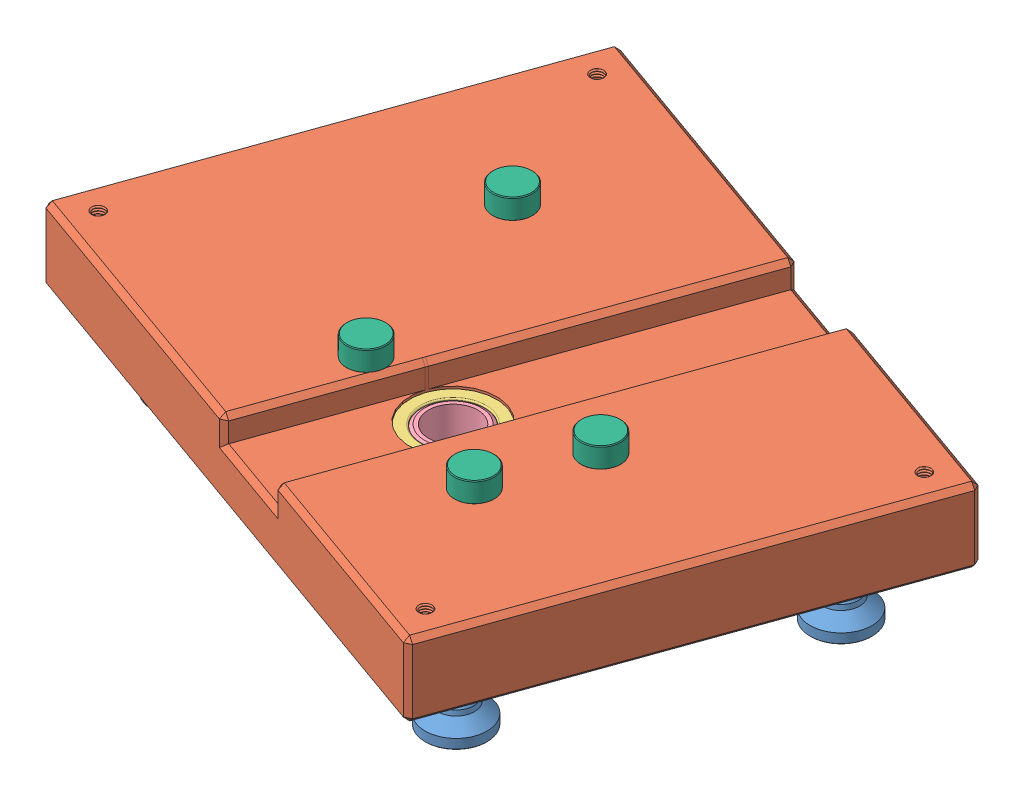
SolidWorks assembly Base Assembly, configuration Default. Lengths in mm.
Overall size (288.96 65.67 252.42).
13 component instances, 6 part files, 20 mates.
Components (placement in the parent):
- 6111K652_Swivel Leveling Mount-1: 6111K652_Swivel Leveling Mount [6111K652] at (23.7661 -3.1667 -158.4984) x (0.999999 0 0.00107) z (-0.00107 0 0.999999)
- Base-1: Base [Default] at (129.9167 0 -185.3091) x (0.942023 0 0.335549) z (0 1 0)
- 16 mm Bushing-1: 16 mm Bushing [Default] at (166.7117 14.5827 -181.7949) x (0 1 0) z (-0.335549 0 0.942023) size (28.57 50.05 51.94)
  - 3556N198_Sleeve for Removable Drill Bushing-1: 3556N198_Sleeve for Removable Drill Bushing [3556N198] at (-5.0577 19.8409 35.2587)
  - 8493A272_Removable Drill Bushing-1: 8493A272_Removable Drill Bushing [8493A272] at (-9.8202 19.8409 35.2587) x (1 0 0) z (0 0.79912 0.601171)
  - 8496A15_Lock Screw for Removable Drill Bushings-1: 8496A15_Lock Screw for Removable Drill Bushings [8496A15] at (-7.9152 33.9177 16.5468)
- 3097N13_Press-Fit Locating and Support Button-1: 3097N13_Press-Fit Locating and Support Button [3097N13] at (173.6646 30 -126.3355) x (1 0 0) z (0 1 0)
- 3097N13_Press-Fit Locating and Support Button-2: 3097N13_Press-Fit Locating and Support Button [3097N13] at (187.0865 30 -164.0164) x (1 0 0) z (0 1 0)
- 3097N13_Press-Fit Locating and Support Button-3: 3097N13_Press-Fit Locating and Support Button [3097N13] at (82.2262 30 -233.214) x (1 0 0) z (0 1 0)
- 3097N13_Press-Fit Locating and Support Button-4: 3097N13_Press-Fit Locating and Support Button [3097N13] at (105.8389 30 -150.495) x (1 0 0) z (0 1 0)
- 6111K652_Swivel Leveling Mount-2: 6111K652_Swivel Leveling Mount [6111K652] at (64.6191 -3.1667 -273.1897) x (0.999999 0 0.00107) z (-0.00107 0 0.999999)
- 6111K652_Swivel Leveling Mount-3: 6111K652_Swivel Leveling Mount [6111K652] at (195.2143 -3.1667 -97.4286) x (0.999999 0 0.00107) z (-0.00107 0 0.999999)
- 6111K652_Swivel Leveling Mount-4: 6111K652_Swivel Leveling Mount [6111K652] at (236.0673 -3.1667 -212.1199) x (0.999999 0 0.00107) z (-0.00107 0 0.999999)
Mates (geometry in assembly coordinates):
- Coincident1: coincident anti-aligned: plane of Base-1 through (129.9167 0 -185.3091) normal (0 -1 0)
- Parallel1: parallel anti-aligned: plane of 6111K652_Swivel Leveling Mount-1 through (23.7587 0 -151.5702) normal (0 1 0); plane of Base-1 through (129.9167 0 -185.3091) normal (0 -1 0)
- Coincident4: coincident anti-aligned: plane of 6111K652_Swivel Leveling Mount-1 through (23.7587 0 -151.5702) normal (0 1 0); plane of Base-1 through (129.9167 0 -185.3091) normal (0 -1 0)
- Distance1: distance = 30 mm: cylinder of 6111K652_Swivel Leveling Mount-1 through (23.7661 -27.6667 -158.4984) axis (0 -1 0) radius 12.5; plane of Base-1 through (-14.561 30 -140.3042) normal (-0.335549 0 0.942023)
- Distance2: distance = 30 mm: cylinder of 6111K652_Swivel Leveling Mount-1 through (23.7661 -27.6667 -158.4984) axis (0 -1 0) radius 12.5; plane of Base-1 through (46.4249 30 -311.5168) normal (-0.942023 0 -0.335549)
- Concentric1: concentric aligned: cylinder of Base-1 through (136.1901 30 -155.2379) axis (0 -1 0) radius 17.5; cylinder of 16 mm Bushing-1/3556N198_Sleeve for Removable Drill Bushing-1 through (136.1901 0 -155.2379) axis (0 -1 0) radius 17.4625
- Coincident5: coincident aligned: plane of Base-1 through (129.9167 0 -185.3091) normal (0 -1 0); circle of 16 mm Bushing-1/3556N198_Sleeve for Removable Drill Bushing-1
- Parallel3: parallel aligned: plane of Base-1 through (274.3944 30 -230.3141) normal (0.942023 0 0.335549); plane of 16 mm Bushing-1/8496A15_Lock Screw for Removable Drill Bushings-1 through (130.1966 -2.8857 -185.6623) normal (0.942023 0 0.335549)
- Coincident7: coincident anti-aligned: plane of Base-1 through (129.9167 30 -185.3091) normal (0 1 0); plane of 3097N13_Press-Fit Locating and Support Button-1 through (173.6646 30 -134.2855) normal (0 -1 0)
- Coincident8: coincident anti-aligned: plane of Base-1 through (129.9167 30 -185.3091) normal (0 1 0); plane of 3097N13_Press-Fit Locating and Support Button-2 through (187.0865 30 -171.9664) normal (0 -1 0)
- Coincident9: coincident anti-aligned: plane of Base-1 through (129.9167 30 -185.3091) normal (0 1 0); plane of 3097N13_Press-Fit Locating and Support Button-4 through (105.8389 30 -158.445) normal (0 -1 0)
- Coincident10: coincident anti-aligned: plane of Base-1 through (129.9167 30 -185.3091) normal (0 1 0); plane of 3097N13_Press-Fit Locating and Support Button-3 through (82.2262 30 -241.164) normal (0 -1 0)
- Distance3: distance = 50 mm: cylinder of 3097N13_Press-Fit Locating and Support Button-1 through (173.6646 42.7 -126.3355) axis (0 1 0) radius 8; plane of Base-1 through (-14.561 30 -140.3042) normal (-0.335549 0 0.942023)
- Distance4: distance = 60 mm: cylinder of 3097N13_Press-Fit Locating and Support Button-1 through (173.6646 42.7 -126.3355) axis (0 1 0) radius 8; plane of Base-1 through (274.3944 30 -230.3141) normal (0.942023 0 0.335549)
- Distance5: distance = 60 mm: cylinder of 3097N13_Press-Fit Locating and Support Button-2 through (187.0865 42.7 -164.0164) axis (0 1 0) radius 8; plane of Base-1 through (274.3944 30 -230.3141) normal (0.942023 0 0.335549)
- Distance6: distance = 90 mm: cylinder of 3097N13_Press-Fit Locating and Support Button-2 through (187.0865 42.7 -164.0164) axis (0 1 0) radius 8; plane of Base-1 through (-14.561 30 -140.3042) normal (-0.335549 0 0.942023)
- Distance7: distance = 60 mm: cylinder of 3097N13_Press-Fit Locating and Support Button-3 through (82.2262 42.7 -233.214) axis (0 1 0) radius 8; plane of Base-1 through (46.4249 30 -311.5168) normal (-0.942023 0 -0.335549)
- Distance8: distance = 120 mm: cylinder of 3097N13_Press-Fit Locating and Support Button-3 through (82.2262 42.7 -233.214) axis (0 1 0) radius 8; plane of Base-1 through (-14.561 30 -140.3042) normal (-0.335549 0 0.942023)
- Distance9: distance = 50 mm: cylinder of 3097N13_Press-Fit Locating and Support Button-4 through (105.8389 42.7 -150.495) axis (0 1 0) radius 8; plane of Base-1 through (-14.561 30 -140.3042) normal (-0.335549 0 0.942023)
- Distance10: distance = 110 mm: cylinder of 3097N13_Press-Fit Locating and Support Button-4 through (105.8389 42.7 -150.495) axis (0 1 0) radius 8; plane of Base-1 through (46.4249 30 -311.5168) normal (-0.942023 0 -0.335549)
